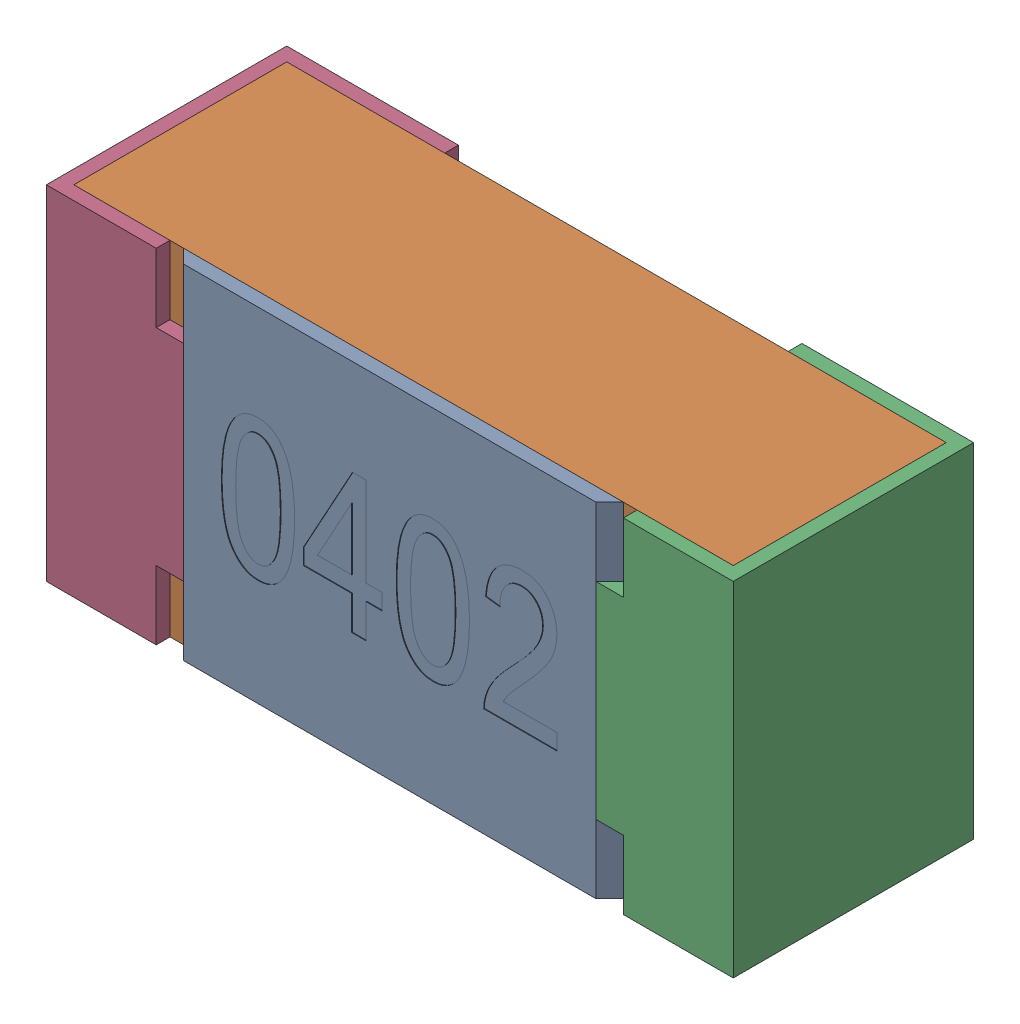
SolidWorks assembly R15, configuration Standard. Lengths in mm.
Overall size (1 0.5 0.35).
5 component instances, 4 part files, 0 mates.
Components (placement in the parent):
- R15-subassembly-1-1: R15-subassembly-1 [Standard] at (-13.1999 -10 0) x (1 0 0) z (0 0 1) size (1 0.5 0.35)
  - User Library-R_0402-1: User Library-R_0402 [Standard] at origin size (0.64 0.5 0.02)
  - User Library-R_0402-1-1: User Library-R_0402-1 [Standard] at origin size (0.96 0.5 0.31)
  - User Library-R_0402-2-1: User Library-R_0402-2 [Standard] at origin size (0.25 0.5 0.35)
  - User Library-R_0402-3-1: User Library-R_0402-3 [Standard] at origin size (0.25 0.5 0.35)
